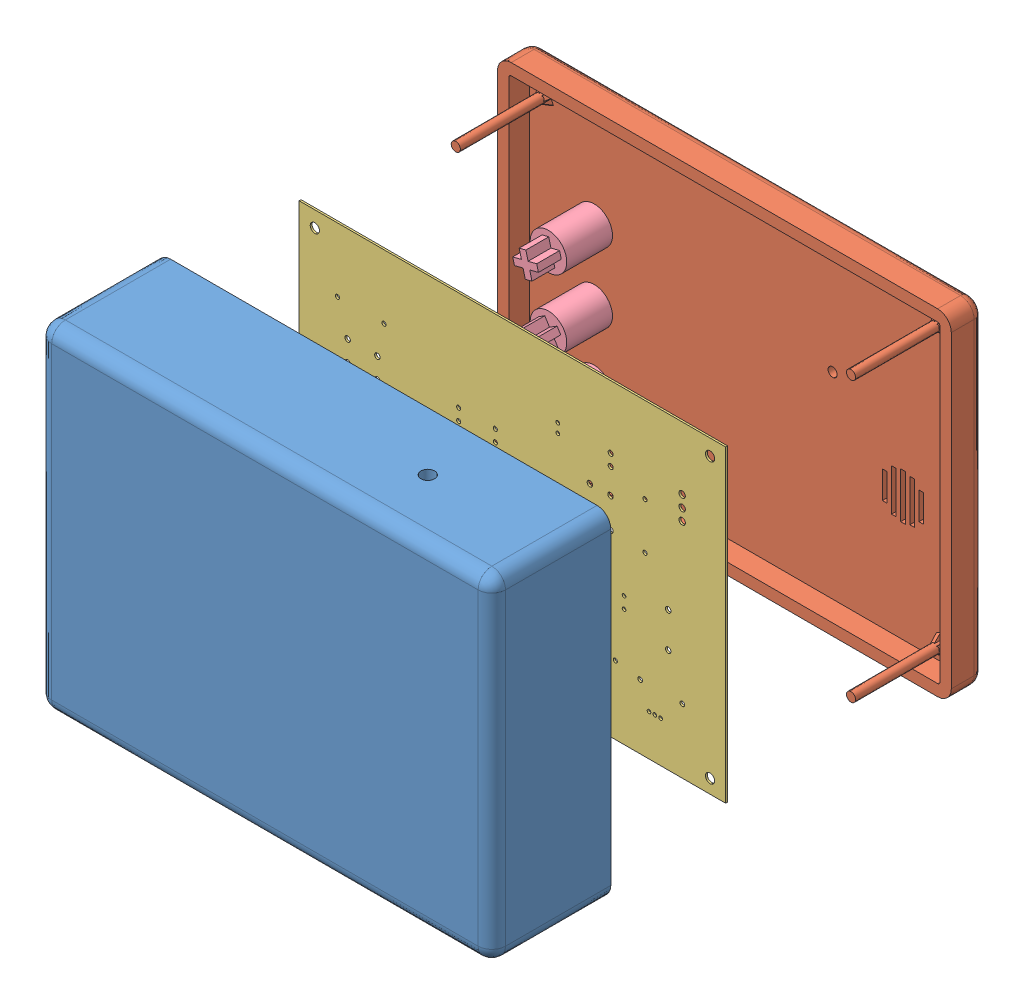
SolidWorks assembly Assem7, configuration Default. Lengths in mm.
Overall size (99.18 73.43 109.91).
8 component instances, 4 part files, 15 mates.
Components (placement in the parent):
- Part7^PCB_Audio Output.step-1: Part7^PCB_Audio Output.step [Default] at (-298.4205 299.0534 83.8862) size (99.18 73.43 26)
- Part8^PCB_Audio Output.step. v1SLDPRT-1: Part8^PCB_Audio Output.step. v1SLDPRT [Default] at (-466.3515 441.9784 -6.5251) x (1 0 0) z (0 0 -1) size (99.18 73.43 23)
- PCB_Audio Output.step-1: PCB_Audio Output.step [Default] at (-298.4483 299.0415 39.3643) x (-1 -0.00005 0) z (0 0 -1) size (93.18 67.43 0.41)
  - Board.step-1: Board.step [Default] at origin size (93.18 67.43 0.41)
    - Open CASCADE STEP translator 6.8 1.1.1.step-1: Open CASCADE STEP translator 6.8 1.1.1.step [Default] at (0 0 -0.4115) size (93.18 67.43 0.41)
- Button-1: Button [Default] at (-415.3334 365.8006 -11.0251) x (0.845808 0.533488 0) z (-0.533488 0.845808 0) size (8 20 8)
- Button-2: Button [Default] at (-415.3334 381.0554 -11.0251) x (0.969687 0.244351 0) z (-0.244351 0.969687 0) size (8 20 8)
- Button-3: Button [Default] at (-415.3334 350.5458 -11.0251) x (-0.923728 -0.383049 0) z (0.383049 -0.923728 0) size (8 20 8)
Mates (geometry in assembly coordinates):
- Coincident2: coincident aligned: plane of Part7^PCB_Audio Output.step-1 through (-332.7955 333.8034 67.8862) normal (1 0 0); plane of Part8^PCB_Audio Output.step. v1SLDPRT-1 through (-332.7955 404.2284 -13.5251) normal (1 0 0)
- Coincident3: coincident aligned: plane of Part7^PCB_Audio Output.step-1 through (-332.7955 333.8034 67.8862) normal (1 0 0); plane of Part8^PCB_Audio Output.step. v1SLDPRT-1 through (-332.7955 404.2284 -13.5251) normal (1 0 0)
- Coincident4: coincident aligned: plane of Part7^PCB_Audio Output.step-1 through (-332.7955 407.2284 67.8862) normal (0 1 0); plane of Part8^PCB_Audio Output.step. v1SLDPRT-1 through (-428.9765 407.2284 -13.5251) normal (0 1 0)
- Concentric5: concentric aligned: cylinder of Part8^PCB_Audio Output.step. v1SLDPRT-1 through (-339.2178 339.8064 -1011.0251) axis (0 0 1) radius 1; cylinder of PCB_Audio Output.step-1/Board.step-1/Open CASCADE STEP translator 6.8 1.1.1.step-1 through (-339.2174 339.8064 39.7757) axis (0 0 1) radius 1.016
- Parallel3: parallel aligned: cylinder of Part8^PCB_Audio Output.step. v1SLDPRT-1 through (-339.2176 400.7677 -1011.0251) axis (0 0 1) radius 1; cylinder of PCB_Audio Output.step-1/Board.step-1/Open CASCADE STEP translator 6.8 1.1.1.step-1 through (-339.2204 400.7664 39.7757) axis (0 0 1) radius 1.016
- Concentric8: concentric aligned: cylinder of Part8^PCB_Audio Output.step. v1SLDPRT-1 through (-339.2178 339.8064 -1011.0251) axis (0 0 1) radius 1; cylinder of PCB_Audio Output.step-1/Board.step-1/Open CASCADE STEP translator 6.8 1.1.1.step-1 through (-339.2174 339.8064 39.7757) axis (0 0 1) radius 1.016
- Parallel4: parallel aligned: cylinder of Part8^PCB_Audio Output.step. v1SLDPRT-1 through (-339.2178 339.8064 -1011.0251) axis (0 0 1) radius 1; cylinder of PCB_Audio Output.step-1/Board.step-1/Open CASCADE STEP translator 6.8 1.1.1.step-1 through (-339.2204 400.7664 39.7757) axis (0 0 1) radius 1.016
- Parallel5: parallel aligned: cylinder of PCB_Audio Output.step-1/Board.step-1/Open CASCADE STEP translator 6.8 1.1.1.step-1 through (-425.5774 339.6751 39.7757) axis (0 0 1) radius 1.016; cylinder of Part8^PCB_Audio Output.step. v1SLDPRT-1 through (-425.5774 339.6751 -1011.0251) axis (0 0 1) radius 1
- Concentric11: concentric aligned: cylinder of Part8^PCB_Audio Output.step. v1SLDPRT-1 through (-425.5774 339.6751 -1011.0251) axis (0 0 1) radius 1; cylinder of PCB_Audio Output.step-1/Board.step-1/Open CASCADE STEP translator 6.8 1.1.1.step-1 through (-425.5774 339.6751 39.7757) axis (0 0 1) radius 1.016
- Concentric14: concentric aligned: cylinder of Part8^PCB_Audio Output.step. v1SLDPRT-1 through (-415.3334 381.0554 -3.5251) axis (0 0 -1) radius 2.5; cylinder of Button-2 through (-415.3334 381.0554 -1.0251) axis (0 0 -1) radius 4
- Coincident6: coincident anti-aligned: plane of Part8^PCB_Audio Output.step. v1SLDPRT-1 through (-428.9765 404.2284 -11.0251) normal (0 0 1); plane of Button-2 through (-415.3334 381.0554 -11.0251) normal (0 0 -1)
- Concentric15: concentric aligned: cylinder of Part8^PCB_Audio Output.step. v1SLDPRT-1 through (-415.3334 365.8006 -3.5251) axis (0 0 -1) radius 2.5; cylinder of Button-1 through (-415.3334 365.8006 -1.0251) axis (0 0 -1) radius 4
- Coincident7: coincident anti-aligned: plane of Part8^PCB_Audio Output.step. v1SLDPRT-1 through (-428.9765 404.2284 -11.0251) normal (0 0 1); plane of Button-1 through (-415.3334 365.8006 -11.0251) normal (0 0 -1)
- Concentric16: concentric aligned: circle of Part8^PCB_Audio Output.step. v1SLDPRT-1; cylinder of Button-3 through (-415.3334 350.5458 -1.0251) axis (0 0 -1) radius 4
- Coincident8: coincident anti-aligned: plane of Part8^PCB_Audio Output.step. v1SLDPRT-1 through (-428.9765 404.2284 -11.0251) normal (0 0 1); plane of Button-3 through (-415.3334 350.5458 -11.0251) normal (0 0 -1)
